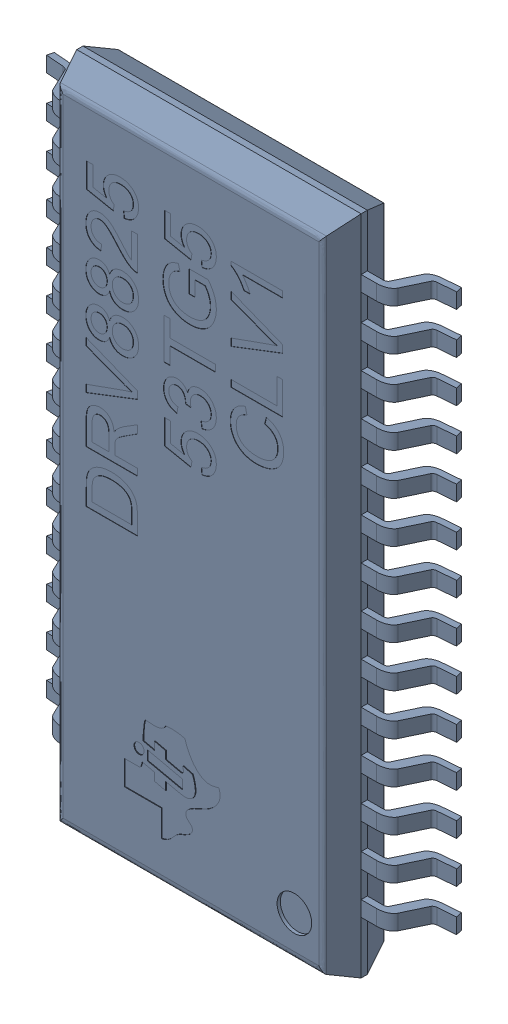
SolidWorks assembly DRV8825 Driver v9 (3), configuration Default. Lengths in mm.
Overall size (6.33 10.21 1.04).
2 component instances, 1 part files, 0 mates.
Components (placement in the parent):
- DRV8825 53TG5 CLV1 (3)-1: DRV8825 53TG5 CLV1 (3) [Default] at (6.5481 7.5317 9.8148) x (1 0 0) z (0 -1 0) size (6.33 1.04 10.21)
  - Package (3)-1: Package (3) [Default] at origin size (6.33 1.04 10.21)
